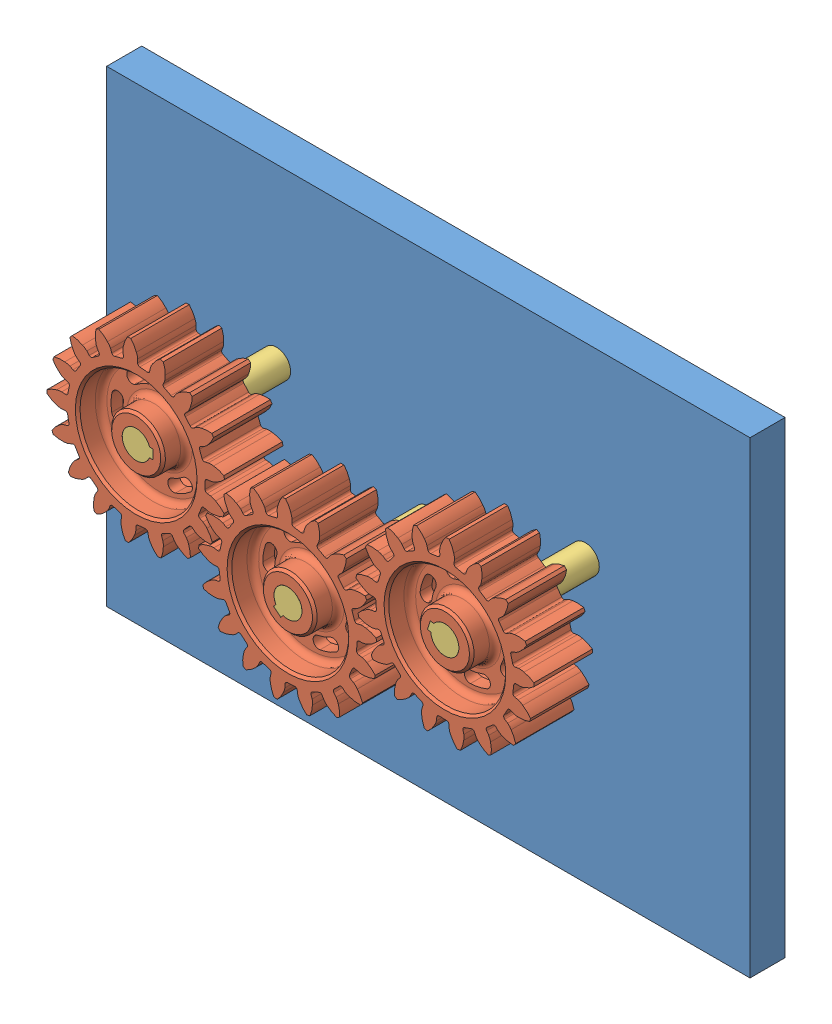
SolidWorks assembly Montagem2, configuration Valor predeterminado. Lengths in mm.
Overall size (550 400 150).
7 component instances, 3 part files, 17 mates.
Components (placement in the parent):
- Peça14.2-1: Peça14.2 [Valor predeterminado] at (-3.9232 9.6118 285) size (550 400 30)
- Peça14-1: Peça14 [Valor predeterminado] at (-133.6456 62.2624 410) x (0.012877 0.999917 0) z (0 0 1) size (152.26 151.63 50)
- Peça14.1-1: Peça14.1 [Valor predeterminado] at (-3.9232 9.6118 435) x (-0.768751 0.639548 0) z (0 0 -1) size (24 26.31 150)
- Peça14-2: Peça14 [Valor predeterminado] at (-3.9232 9.6118 410) x (0.768751 -0.639548 0) z (0 0 1) size (152.26 151.63 50)
- Peça14.1-2: Peça14.1 [Valor predeterminado] at (-133.6456 62.2624 435) x (-0.012877 -0.999917 0) z (0 0 -1) size (24 26.31 150)
- Peça14-3: Peça14 [Valor predeterminado] at (130.2586 49.5522 410) x (-0.301145 -0.953578 0) z (0 0 1) size (152.26 151.63 50)
- Peça14.1-3: Peça14.1 [Valor predeterminado] at (130.2586 49.5522 435) x (0.301145 0.953578 0) z (0 0 -1) size (24 26.31 150)
Mates (geometry in assembly coordinates):
- Concêntrico1: concentric anti-aligned: cylinder of Peça14.2-1 through (-133.6456 62.2624 315) axis (0 0 -1) radius 12; cylinder of Peça14.1-2 through (-133.6456 62.2624 285) axis (0 0 1) radius 12
- Concêntrico2: concentric anti-aligned: cylinder of Peça14.2-1 through (-3.9232 9.6118 315) axis (0 0 -1) radius 12; cylinder of Peça14.1-1 through (-3.9232 9.6118 285) axis (0 0 1) radius 12
- Coincidente1: coincident aligned: plane of Peça14.2-1 through (-3.9232 9.6118 285) normal (0 0 -1); circle of Peça14.1-1
- Coincidente2: coincident aligned: plane of Peça14.2-1 through (-3.9232 9.6118 285) normal (0 0 -1); plane of Peça14.1-2 through (-133.6456 62.2624 285) normal (0 0 -1)
- Coincidente3: coincident anti-aligned: plane of Peça14-1 through (-119.3331 62.078 435) normal (-0.999917 0.012877 0); plane of Peça14.1-2 through (-119.3331 62.078 385) normal (0.999917 -0.012877 0)
- Coincidente4: coincident anti-aligned: plane of Peça14.1-1 through (-13.0775 -1.3919 385) normal (-0.639548 -0.768751 0); plane of Peça14-2 through (-13.0775 -1.3919 435) normal (0.639548 0.768751 0)
- Coincidente5: coincident anti-aligned: plane of Peça14-1 through (-133.6972 58.2627 435) normal (0.012877 0.999917 0); plane of Peça14.1-2 through (-133.6972 58.2627 385) normal (-0.012877 -0.999917 0)
- Coincidente6: coincident anti-aligned: plane of Peça14.1-1 through (-6.9982 12.17 385) normal (-0.768751 0.639548 0); plane of Peça14-2 through (-6.9982 12.17 435) normal (0.768751 -0.639548 0)
- Coincidente7: coincident aligned: plane of Peça14.1-1 through (-3.9232 9.6118 435) normal (0 0 1); plane of Peça14-2 through (-3.9232 9.6118 435) normal (0 0 1)
- Coincidente8: coincident aligned: plane of Peça14-1 through (-133.6456 62.2624 435) normal (0 0 1); plane of Peça14.1-2 through (-133.6456 62.2624 435) normal (0 0 1)
- Posic. engrenagem1: gear = 46 : 46 mm: cylinder of Peça14-2 through (-3.9232 9.6118 435) axis (0 0 -1) radius 23; cylinder of Peça14-1 through (-133.6456 62.2624 435) axis (0 0 -1) radius 23
- Concêntrico3: concentric anti-aligned: cylinder of Peça14.2-1 through (130.2586 49.5522 315) axis (0 0 -1) radius 12; cylinder of Peça14.1-3 through (130.2586 49.5522 285) axis (0 0 1) radius 12
- Coincidente9: coincident aligned: plane of Peça14.2-1 through (-3.9232 9.6118 285) normal (0 0 -1); plane of Peça14.1-3 through (130.2586 49.5522 285) normal (0 0 -1)
- Coincidente10: coincident anti-aligned: plane of Peça14-3 through (116.6094 53.8627 435) normal (0.953578 -0.301145 0); plane of Peça14.1-3 through (116.6094 53.8627 385) normal (-0.953578 0.301145 0)
- Coincidente11: coincident anti-aligned: plane of Peça14-3 through (131.4632 53.3665 435) normal (-0.301145 -0.953578 0); plane of Peça14.1-3 through (131.4632 53.3665 385) normal (0.301145 0.953578 0)
- Coincidente12: coincident aligned: plane of Peça14-3 through (130.2586 49.5522 435) normal (0 0 1); plane of Peça14.1-3 through (130.2586 49.5522 435) normal (0 0 1)
- Posic. engrenagem2: gear = 46 : 46 mm: cylinder of Peça14-3 through (130.2586 49.5522 435) axis (0 0 -1) radius 23; cylinder of Peça14-2 through (-3.9232 9.6118 435) axis (0 0 -1) radius 23
